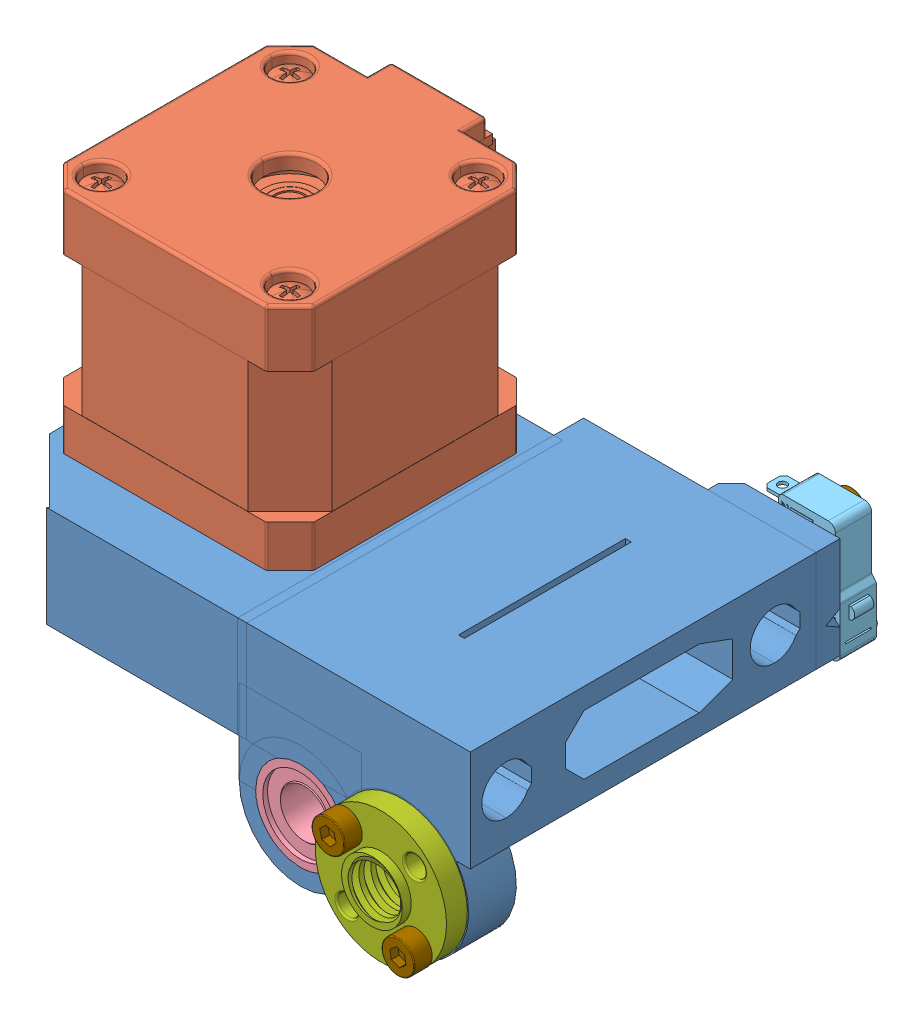
SolidWorks assembly Assembly x-axis left, configuration Valor predeterminado. Lengths in mm.
Overall size (85.56 77.47 77.9).
16 component instances, 9 part files, 38 mates.
Components (placement in the parent):
- x-end-motor-1: x-end-motor [Valor predeterminado] at (-28.5 -15 0) x (0 -1 0) z (0 0 -1) size (34.73 81.5 62)
- Stepper motor Nema 17-1: Stepper motor Nema 17 [Valor predeterminado] at (-36.3722 21 -25.9956) x (0 1 0) z (0 0 -1) size (62.01 42.01 48.01)
- Screw DIN 912 - M3 x 20 --- 20N-1: Screw DIN 912 - M3 x 20 --- 20N [Valor predeterminado] at (-76 -10 -14.75) x (0 -1 0) z (-0.89717 0 -0.441685) size (23 5.5 5.5)
- Screw DIN 912 - M3 x 20 --- 20N-2: Screw DIN 912 - M3 x 20 --- 20N [Valor predeterminado] at (-45 -10 -14.75) x (0 -1 0) z (-0.89717 0 -0.441685) size (23 5.5 5.5)
- Screw DIN 912 - M3 x 20 --- 20N-3: Screw DIN 912 - M3 x 20 --- 20N [Valor predeterminado] at (-45 -10 -45.75) x (0 -1 0) z (-0.89717 0 -0.441685) size (23 5.5 5.5)
- Linear bearing LM8UU-1: Linear bearing LM8UU [Valor predeterminado] at (-36.5476 -6.4908 -17.5556) x (0 0 -1) z (0.968493 0.249041 0) size (24 15 15)
- Linear bearing LM8UU-2: Linear bearing LM8UU [Valor predeterminado] at (-36.5476 -6.4908 -51.5556) x (0 0 -1) z (0.968493 0.249041 0) size (24 15 15)
- Microswitch without leaver - KW11-3Z 5A 250VAC-1: Microswitch without leaver - KW11-3Z 5A 250VAC [Valor predeterminado] at (-5.2875 -0.1625 -65.2) x (0 1 0) z (0 0 -1) size (19.85 15.2 6.4)
- Pulley GT2 20T-1: Pulley GT2 20T [Valor predeterminado] at (-60.5 -10.95 -30.25) x (0 1 0) z (0.980611 0 -0.195965) size (16 16 16)
- LeadScrew Nut - 8 x 2-1: LeadScrew Nut - 8 x 2 [Default] at (-11.5 -15 3.5) x (0.707107 0.707107 0) z (0 0 1) size (22 22 16.05)
- Nut DIN 934 - M3-1: Nut DIN 934 - M3 [Valor predeterminado] at (-5.631 -20.869 -7.2) x (0 0 -1) z (0.707107 0.707107 0) size (2.4 5.5 6.35)
- Nut DIN 934 - M3-2: Nut DIN 934 - M3 [Valor predeterminado] at (-17.369 -9.131 -7.2) x (0 0 -1) z (0.258819 0.965926 0) size (2.4 5.5 6.35)
- Screw DIN 912 - M3 x 12 --- 12N-1: Screw DIN 912 - M3 x 12 --- 12N [Valor predeterminado] at (-5.631 -20.869 6.5) x (0 0 1) z (-0.933618 0.358271 0) size (15 5.5 5.5)
- Screw DIN 912 - M3 x 12 --- 12N-2: Screw DIN 912 - M3 x 12 --- 12N [Valor predeterminado] at (-17.369 -9.131 6.5) x (0 0 1) z (-0.253715 0.967279 0) size (15 5.5 5.5)
- Screw DIN 912 - M3 x 12 --- 12N-3: Screw DIN 912 - M3 x 12 --- 12N [Valor predeterminado] at (-7.5 4.775 -71.4) x (0 0 -1) z (0.333183 0.942862 0) size (15 5.5 5.5)
- Screw DIN 912 - M3 x 12 --- 12N-4: Screw DIN 912 - M3 x 12 --- 12N [Valor predeterminado] at (-7.5 -4.75 -71.4) x (0 0 -1) z (0.744402 0.667732 0) size (15 5.5 5.5)
Mates (geometry in assembly coordinates):
- Coincidente1: coincident: plane of assembly through (0 0 0) normal (0 0 1); plane of x-end-motor-1 through (0 8.5 0) normal (0 0 1); plane of assembly
- Coincidente2: coincident: plane of assembly through (0 0 0) normal (1 0 0); plane of x-end-motor-1 through (0 8.5 0) normal (1 0 0); plane of assembly
- Simétrico1: symmetric: plane of assembly; plane of assembly; plane of x-end-motor-1 through (4.5 -5 -16) normal (0 1 0); plane of x-end-motor-1 through (4.5 5 -16) normal (0 -1 0); plane of assembly
- Coincidente3: coincident: plane of assembly; plane of assembly; plane of x-end-motor-1 through (-37.5 8.5 0) normal (0 1 0); plane of Stepper motor Nema 17-1 through (-60.5 8.5 -30.25) normal (0 -1 0)
- Paralelo1: parallel: plane of assembly; plane of assembly; plane of x-end-motor-1 through (-37.5 8.5 0) normal (0 0 1); plane of Stepper motor Nema 17-1 through (-81.5 15.5 -9.25) normal (0 0 1)
- Concêntrico1: concentric: cylinder of assembly; cylinder of assembly; cylinder of x-end-motor-1 through (-45 -34 -14.75) axis (0 1 0) radius 2; cylinder of Stepper motor Nema 17-1 through (-45 12 -14.75) axis (0 -1 0) radius 1.5
- Concêntrico2: concentric: cylinder of assembly; cylinder of assembly; cylinder of x-end-motor-1 through (-76 -34 -14.75) axis (0 1 0) radius 2; cylinder of Screw DIN 912 - M3 x 20 --- 20N-1 through (-76 -10 -14.75) axis (0 -1 0) radius 1.5
- Coincidente5: coincident: plane of assembly; plane of assembly; plane of x-end-motor-1 through (-76 -7 -14.75) normal (0 -1 0); plane of Screw DIN 912 - M3 x 20 --- 20N-1 through (-77.2146 -7 -12.2828) normal (0 1 0)
- Concêntrico3: concentric: cylinder of assembly; cylinder of assembly; cylinder of x-end-motor-1 through (-45 -34 -45.75) axis (0 1 0) radius 2; cylinder of Screw DIN 912 - M3 x 20 --- 20N-3 through (-45 -10 -45.75) axis (0 -1 0) radius 1.5
- Concêntrico4: concentric: cylinder of assembly; cylinder of assembly; cylinder of x-end-motor-1 through (-45 -34 -14.75) axis (0 1 0) radius 2; cylinder of Screw DIN 912 - M3 x 20 --- 20N-2 through (-45 -10 -14.75) axis (0 -1 0) radius 1.5
- Coincidente6: coincident: plane of assembly; plane of assembly; plane of x-end-motor-1 through (-45 -7 -45.75) normal (0 -1 0); plane of Screw DIN 912 - M3 x 20 --- 20N-3 through (-46.2146 -7 -43.2828) normal (0 1 0)
- Coincidente7: coincident: plane of assembly; plane of assembly; plane of x-end-motor-1 through (-45 -7 -14.75) normal (0 -1 0); plane of Screw DIN 912 - M3 x 20 --- 20N-2 through (-46.2146 -7 -12.2828) normal (0 1 0)
- Concêntrico5: concentric: cylinder of assembly; cylinder of assembly; cylinder of x-end-motor-1 through (-28.5 -15 1) axis (0 0 -1) radius 7.4933; cylinder of Linear bearing LM8UU-1 through (-28.5 -15 -12) axis (0 0 -1) radius 7.5
- Coincidente8: coincident: plane of assembly; plane of assembly; plane of x-end-motor-1 through (0 8.5 0) normal (0 0 1); plane of Linear bearing LM8UU-1 through (-28.0151 -22.4843 0) normal (0 0 1)
- Concêntrico6: concentric: cylinder of assembly; cylinder of assembly; cylinder of x-end-motor-1 through (-28.5 -15 1) axis (0 0 -1) radius 7.4933; cylinder of Linear bearing LM8UU-2 through (-28.5 -15 -46) axis (0 0 -1) radius 7.5
- Coincidente9: coincident: plane of assembly; plane of assembly; plane of x-end-motor-1 through (-28.5 -15 -58) normal (0 0 -1); plane of Linear bearing LM8UU-2 through (-28.0927 -21.2868 -58) normal (0 0 -1)
- Concêntrico7: concentric: cylinder of assembly; cylinder of assembly; cylinder of x-end-motor-1 through (-7.5 -4.75 -53) axis (0 0 -1) radius 1.3; cylinder of Microswitch without leaver - KW11-3Z 5A 250VAC-1 through (-7.5 -4.75 -68.4) axis (0 0 1) radius 1.175
- Coincidente10: coincident: plane of assembly; plane of assembly; plane of x-end-motor-1 through (0 8.5 -62) normal (0 0 -1); plane of Microswitch without leaver - KW11-3Z 5A 250VAC-1 through (-8.6396 -4.75 -62) normal (0 0 1)
- Paralelo2: parallel: plane of assembly; plane of assembly; plane of x-end-motor-1 through (0 8.5 -58) normal (1 0 0); plane of Microswitch without leaver - KW11-3Z 5A 250VAC-1 through (-0.9375 9.9375 -65.2) normal (1 0 0)
- Concêntrico9: concentric: cylinder of assembly; cylinder of assembly; cylinder of Stepper motor Nema 17-1 through (-60.5 12.9 -30.25) axis (0 1 0) radius 2.5; cylinder of Pulley GT2 20T-1 through (-60.5 -10.95 -30.25) axis (0 1 0) radius 2.5
- Coincidente13: coincident: plane of assembly through (0 0 0) normal (0 1 0); plane of Pulley GT2 20T-1 through (-60.5 0 -30.25) normal (0 1 0); plane of assembly
- Concêntrico10: concentric: cylinder of assembly; cylinder of assembly; cylinder of x-end-motor-1 through (-11.5 -15 1) axis (0 0 -1) radius 5.5555; cylinder of LeadScrew Nut - 8 x 2-1 through (-11.5 -15 0) axis (0 0 1) radius 11
- Coincidente15: coincident: plane of assembly; plane of assembly; plane of x-end-motor-1 through (-11.5 -15 0) normal (0 0 1); plane of LeadScrew Nut - 8 x 2-1 through (-11.5 -15 0) normal (0 0 -1)
- Concêntrico11: concentric: cylinder of assembly; cylinder of assembly; cylinder of x-end-motor-1 through (-5.631 -20.869 1) axis (0 0 -1) radius 1.7; cylinder of Nut DIN 934 - M3-1 through (-5.631 -20.869 -8.4) axis (0 0 1) radius 1.25
- Paralelo3: parallel: line of assembly; plane of assembly; line of x-end-motor-1 through (-3.2976 -18.5355 -8) axis (-0.965926 0.258819 0); plane of Nut DIN 934 - M3-1 through (-4.8092 -23.9362 -8.4) normal (-0.258819 -0.965926 0)
- Coincidente17: coincident: plane of assembly; plane of assembly; plane of x-end-motor-1 through (-5.631 -20.869 -6) normal (0 0 -1); plane of Nut DIN 934 - M3-1 through (-4.8092 -23.9362 -6) normal (0 0 1)
- Concêntrico12: concentric: cylinder of assembly; cylinder of assembly; cylinder of x-end-motor-1 through (-17.369 -9.131 1) axis (0 0 -1) radius 1.7; cylinder of Nut DIN 934 - M3-2 through (-17.369 -9.131 -8.4) axis (0 0 1) radius 1.25
- Paralelo4: parallel: plane of assembly; plane of assembly; plane of x-end-motor-1 through (-18.3386 -12.0806 -6) normal (0.707107 0.707107 0); plane of Nut DIN 934 - M3-2 through (-16.5471 -6.0638 -8.4) normal (0.707107 0.707107 0)
- Coincidente19: coincident: plane of assembly; plane of assembly; plane of x-end-motor-1 through (-17.5104 -8.9896 -6) normal (0 0 -1); plane of Nut DIN 934 - M3-2 through (-15.1236 -11.3764 -6) normal (0 0 1)
- Concêntrico13: concentric: cylinder of assembly; cylinder of assembly; cylinder of x-end-motor-1 through (-5.631 -20.869 1) axis (0 0 -1) radius 1.7; cylinder of Screw DIN 912 - M3 x 12 --- 12N-1 through (-5.631 -20.869 6.5) axis (0 0 1) radius 1.5
- Coincidente20: coincident: plane of assembly; plane of assembly; plane of LeadScrew Nut - 8 x 2-1 through (-11.5 -15 3.5) normal (0 0 1); plane of Screw DIN 912 - M3 x 12 --- 12N-1 through (-4.6458 -18.3015 3.5) normal (0 0 -1)
- Concêntrico14: concentric: cylinder of assembly; cylinder of assembly; cylinder of x-end-motor-1 through (-17.369 -9.131 1) axis (0 0 -1) radius 1.7; cylinder of Screw DIN 912 - M3 x 12 --- 12N-2 through (-17.369 -9.131 6.5) axis (0 0 1) radius 1.5
- Coincidente21: coincident: plane of assembly; plane of assembly; plane of LeadScrew Nut - 8 x 2-1 through (-11.5 -15 3.5) normal (0 0 1); plane of Screw DIN 912 - M3 x 12 --- 12N-2 through (-14.709 -8.4333 3.5) normal (0 0 -1)
- Coincidente22: coincident: plane of assembly; plane of assembly; plane of x-end-motor-1 through (-20 -6.5 0) normal (-0.707107 -0.707107 0); plane of LeadScrew Nut - 8 x 2-1 through (-11.5 -15 3.5) normal (-0.707107 -0.707107 0)
- Concêntrico15: concentric: cylinder of assembly; cylinder of assembly; cylinder of Microswitch without leaver - KW11-3Z 5A 250VAC-1 through (-7.5 4.775 -68.4) axis (0 0 1) radius 1.175; cylinder of Screw DIN 912 - M3 x 12 --- 12N-3 through (-7.5 4.775 -71.4) axis (0 0 -1) radius 1.5
- Coincidente23: coincident: plane of assembly; plane of assembly; plane of Microswitch without leaver - KW11-3Z 5A 250VAC-1 through (-8.6396 4.775 -68.4) normal (0 0 -1); plane of Screw DIN 912 - M3 x 12 --- 12N-3 through (-10.0929 5.6913 -68.4) normal (0 0 1)
- Concêntrico16: concentric: cylinder of assembly; cylinder of assembly; cylinder of Microswitch without leaver - KW11-3Z 5A 250VAC-1 through (-7.5 -4.75 -68.4) axis (0 0 1) radius 1.175; cylinder of Screw DIN 912 - M3 x 12 --- 12N-4 through (-7.5 -4.75 -71.4) axis (0 0 -1) radius 1.5
- Coincidente24: coincident: plane of assembly; plane of assembly; plane of Microswitch without leaver - KW11-3Z 5A 250VAC-1 through (-8.6396 -4.75 -68.4) normal (0 0 -1); plane of Screw DIN 912 - M3 x 12 --- 12N-4 through (-9.3363 -2.7029 -68.4) normal (0 0 1)
